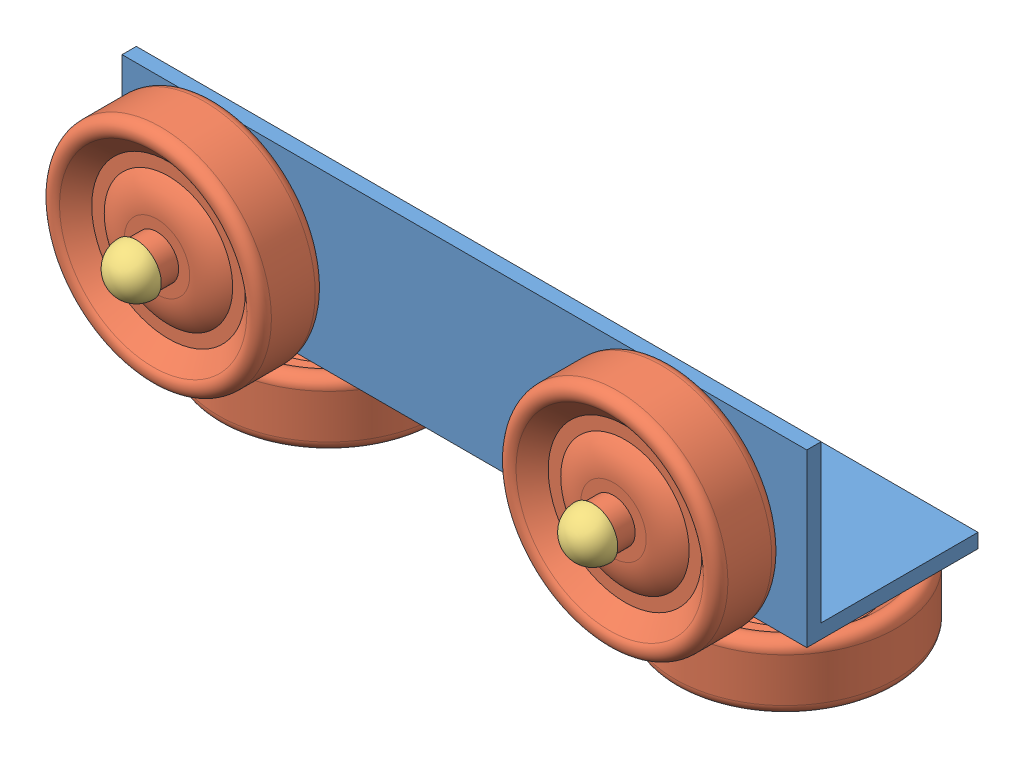
SolidWorks assembly roller, configuration Default. Lengths in mm.
Overall size (152.4 73.02 73.02).
14 component instances, 5 part files, 26 mates.
Components (placement in the parent):
- wheelMount-1: wheelMount [Default] at (-14.6508 88.2462 148.8083) size (152.4 38.1 38.1)
- 9960T510_SKATE WHEEL-1: 9960T510_SKATE WHEEL [9960T51] at (112.3492 108.8837 160.7145) size (49.21 49.21 20.64)
- 9960T510_SKATE WHEEL-2: 9960T510_SKATE WHEEL [9960T51] at (10.7492 108.8837 160.7145) size (49.21 49.21 20.64)
- 9960T510_SKATE WHEEL-3: 9960T510_SKATE WHEEL [9960T51] at (112.3492 76.34 128.1708) x (1 0 0) z (0 1 0) size (49.21 49.21 20.64)
- 9960T510_SKATE WHEEL-4: 9960T510_SKATE WHEEL [9960T51] at (10.7492 76.34 128.1708) x (1 0 0) z (0 1 0) size (49.21 49.21 20.64)
- .2520-1: .2520 [Default] at (10.7492 108.8837 136.1083) x (-0.214028 0.976828 0) z (0.976828 0.214028 0) size (11.1 40.47 11.1)
- .2520-2: .2520 [Default] at (112.3492 100.9462 128.1708) x (-0.214028 0 0.976828) z (0.976828 0 0.214028) size (11.1 40.47 11.1)
- .2520-3: .2520 [Default] at (112.3492 108.8837 136.1083) x (-0.214028 0.976828 0) z (0.976828 0.214028 0) size (11.1 40.47 11.1)
- .2520-4: .2520 [Default] at (10.7492 100.9462 128.1708) x (-0.214028 0 0.976828) z (0.976828 0 0.214028) size (11.1 40.47 11.1)
- washer-1: washer [Default] at (10.7492 108.8837 149.8243) x (0.936378 0.350993 0) z (-0.350993 0.936378 0) size (17.48 1.02 17.48)
- washer-2: washer [Default] at (10.7492 87.2302 128.1708) x (0.936378 0 0.350993) z (-0.350993 0 0.936378) size (17.48 1.02 17.48)
- washer-3: washer [Default] at (112.3492 87.2302 128.1708) x (0.936378 0 0.350993) z (-0.350993 0 0.936378) size (17.48 1.02 17.48)
- washer-4: washer [Default] at (112.3492 108.8837 149.8243) x (0.936378 0.350993 0) z (-0.350993 0.936378 0) size (17.48 1.02 17.48)
- nut-1: nut [Default] at (10.7492 91.4212 128.1708) size (12.83 8.12 11.11)
Mates (geometry in assembly coordinates):
- Concentric6: concentric aligned: cylinder of wheelMount-1 through (112.3492 108.8837 148.8083) axis (0 0 -1) radius 3.175; cylinder of 9960T510_SKATE WHEEL-1 through (112.3492 108.8837 150.3958) axis (0 0 -1) radius 3.175
- Concentric7: concentric aligned: cylinder of wheelMount-1 through (10.7492 108.8837 148.8083) axis (0 0 -1) radius 3.175; cylinder of 9960T510_SKATE WHEEL-2 through (10.7492 108.8837 150.3958) axis (0 0 -1) radius 3.175
- Concentric8: concentric anti-aligned: cylinder of wheelMount-1 through (10.7492 88.2462 128.1708) axis (0 1 0) radius 3.175; cylinder of 9960T510_SKATE WHEEL-4 through (10.7492 66.0212 128.1708) axis (0 -1 0) radius 3.175
- Concentric9: concentric anti-aligned: cylinder of wheelMount-1 through (112.3492 88.2462 128.1708) axis (0 1 0) radius 3.175; cylinder of 9960T510_SKATE WHEEL-3 through (112.3492 66.0212 128.1708) axis (0 -1 0) radius 3.175
- Distance3: distance = 1.5875 mm anti-aligned: plane of 9960T510_SKATE WHEEL-1 through (112.3492 105.7087 150.3958) normal (0 0 -1); plane of wheelMount-1 through (137.7492 88.2462 148.8083) normal (0 0 1)
- Distance4: distance = 1.5875 mm anti-aligned: plane of 9960T510_SKATE WHEEL-3 through (112.3492 86.6587 131.3458) normal (0 1 0); plane of wheelMount-1 through (137.7492 88.2462 110.7083) normal (0 -1 0)
- Coincident7: coincident anti-aligned: plane of 9960T510_SKATE WHEEL-3 through (112.3492 86.6587 131.3458) normal (0 1 0); circle of 9960T510_SKATE WHEEL-4
- Coincident8: coincident aligned: plane of 9960T510_SKATE WHEEL-1 through (112.3492 105.7087 150.3958) normal (0 0 -1); plane of 9960T510_SKATE WHEEL-2 through (10.7492 105.7087 150.3958) normal (0 0 -1)
- Concentric10: concentric aligned: cylinder of 9960T510_SKATE WHEEL-2 through (10.7492 108.8837 150.3958) axis (0 0 -1) radius 3.175; cylinder of .2520-1 through (10.7492 108.8837 136.1083) axis (0 0 -1) radius 3.175
- Coincident9: coincident anti-aligned: plane of 9960T510_SKATE WHEEL-2 through (10.7492 105.7087 171.0333) normal (0 0 1); plane of .2520-1 through (10.0696 111.9851 171.0333) normal (0 0 -1)
- Concentric11: concentric anti-aligned: cylinder of 9960T510_SKATE WHEEL-4 through (10.7492 66.0212 128.1708) axis (0 -1 0) radius 3.175; cylinder of .2520-4 through (10.7492 100.9462 128.1708) axis (0 1 0) radius 3.175
- Coincident10: coincident anti-aligned: plane of 9960T510_SKATE WHEEL-4 through (10.7492 66.0212 131.3458) normal (0 -1 0); plane of .2520-4 through (10.0696 66.0212 131.2722) normal (0 1 0)
- Concentric12: concentric anti-aligned: cylinder of 9960T510_SKATE WHEEL-3 through (112.3492 66.0212 128.1708) axis (0 -1 0) radius 3.175; cylinder of .2520-2 through (112.3492 100.9462 128.1708) axis (0 1 0) radius 3.175
- Coincident11: coincident anti-aligned: plane of 9960T510_SKATE WHEEL-3 through (112.3492 66.0212 131.3458) normal (0 -1 0); plane of .2520-2 through (111.6696 66.0212 131.2722) normal (0 1 0)
- Concentric13: concentric aligned: cylinder of 9960T510_SKATE WHEEL-1 through (112.3492 108.8837 150.3958) axis (0 0 -1) radius 3.175; cylinder of .2520-3 through (112.3492 108.8837 136.1083) axis (0 0 -1) radius 3.175
- Coincident12: coincident aligned: circle of 9960T510_SKATE WHEEL-1; plane of .2520-3 through (111.6696 111.9851 171.0333) normal (0 0 -1)
- Concentric14: concentric anti-aligned: cylinder of .2520-1 through (10.7492 108.8837 136.1083) axis (0 0 -1) radius 3.175; cylinder of washer-1 through (10.7492 108.8837 148.8083) axis (0 0 1) radius 3.3655
- Coincident13: coincident anti-aligned: plane of wheelMount-1 through (137.7492 88.2462 148.8083) normal (0 0 1); plane of washer-1 through (10.7492 108.8837 148.8083) normal (0 0 -1)
- Concentric15: concentric anti-aligned: cylinder of .2520-4 through (10.7492 100.9462 128.1708) axis (0 1 0) radius 3.175; cylinder of washer-2 through (10.7492 88.2462 128.1708) axis (0 -1 0) radius 3.3655
- Concentric16: concentric anti-aligned: cylinder of .2520-2 through (112.3492 100.9462 128.1708) axis (0 1 0) radius 3.175; cylinder of washer-3 through (112.3492 88.2462 128.1708) axis (0 -1 0) radius 3.3655
- Concentric17: concentric anti-aligned: cylinder of .2520-3 through (112.3492 108.8837 136.1083) axis (0 0 -1) radius 3.175; cylinder of washer-4 through (112.3492 108.8837 148.8083) axis (0 0 1) radius 3.3655
- Coincident14: coincident anti-aligned: plane of wheelMount-1 through (137.7492 88.2462 110.7083) normal (0 -1 0); plane of washer-3 through (112.3492 88.2462 128.1708) normal (0 1 0)
- Coincident15: coincident anti-aligned: plane of wheelMount-1 through (137.7492 88.2462 110.7083) normal (0 -1 0); plane of washer-2 through (10.7492 88.2462 128.1708) normal (0 1 0)
- Coincident16: coincident anti-aligned: plane of wheelMount-1 through (137.7492 88.2462 148.8083) normal (0 0 1); plane of washer-4 through (112.3492 108.8837 148.8083) normal (0 0 -1)
- Concentric18: concentric anti-aligned: cylinder of .2520-4 through (10.7492 100.9462 128.1708) axis (0 1 0) radius 3.175; cylinder of nut-1 through (10.7492 99.3587 128.1708) axis (0 -1 0) radius 3.175
- Coincident17: coincident anti-aligned: plane of wheelMount-1 through (137.7492 91.4212 145.6333) normal (0 1 0); plane of nut-1 through (10.7492 91.4212 128.1708) normal (0 -1 0)
